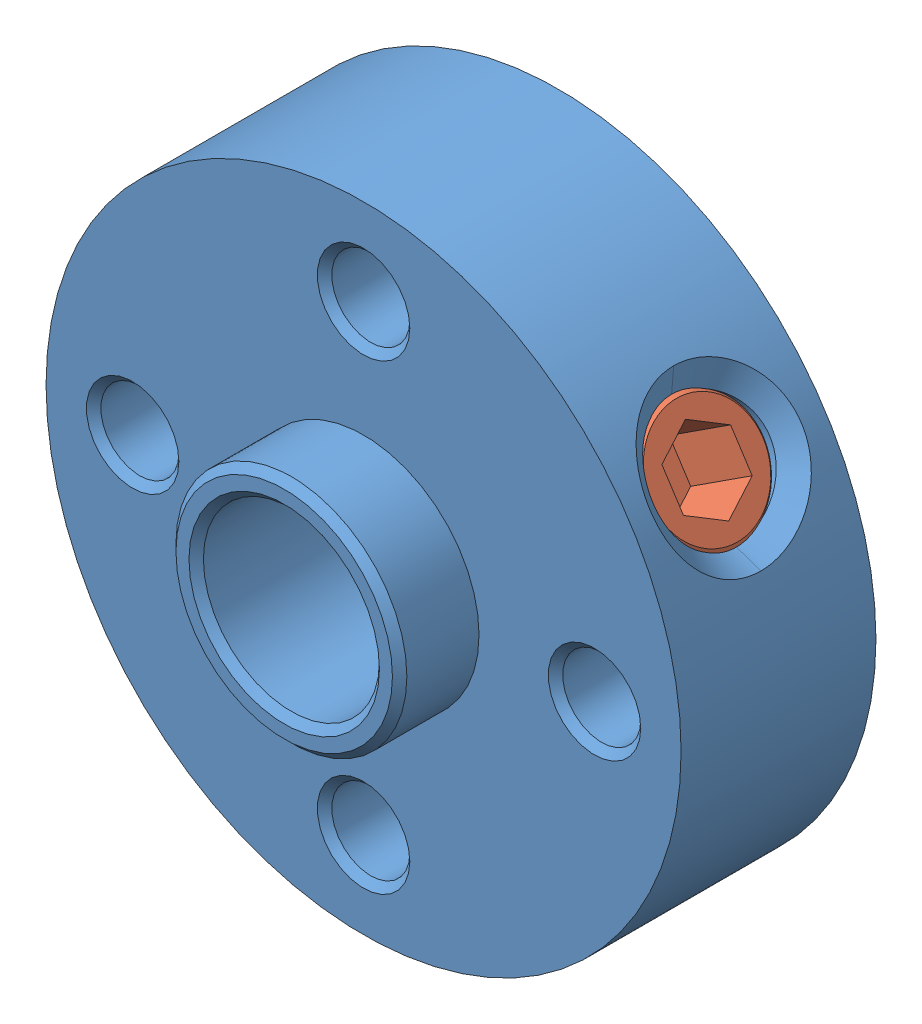
SolidWorks assembly tetrix_739079_2012, configuration Default. Lengths in mm.
Overall size (22 22 9.5).
2 component instances, 2 part files, 0 mates.
Components (placement in the parent):
- TETRIX_739079_COLLAR_2012-1: TETRIX_739079_COLLAR_2012 [Default] at origin size (22 22 9.5)
- TETRIX_739079_SCREW_2012-1: TETRIX_739079_SCREW_2012 [Default] at (8.5735 5.5677 -3.325) x (-0.544639 0.838671 0) z (0 0 1) size (4.83 7.94 4.83)
